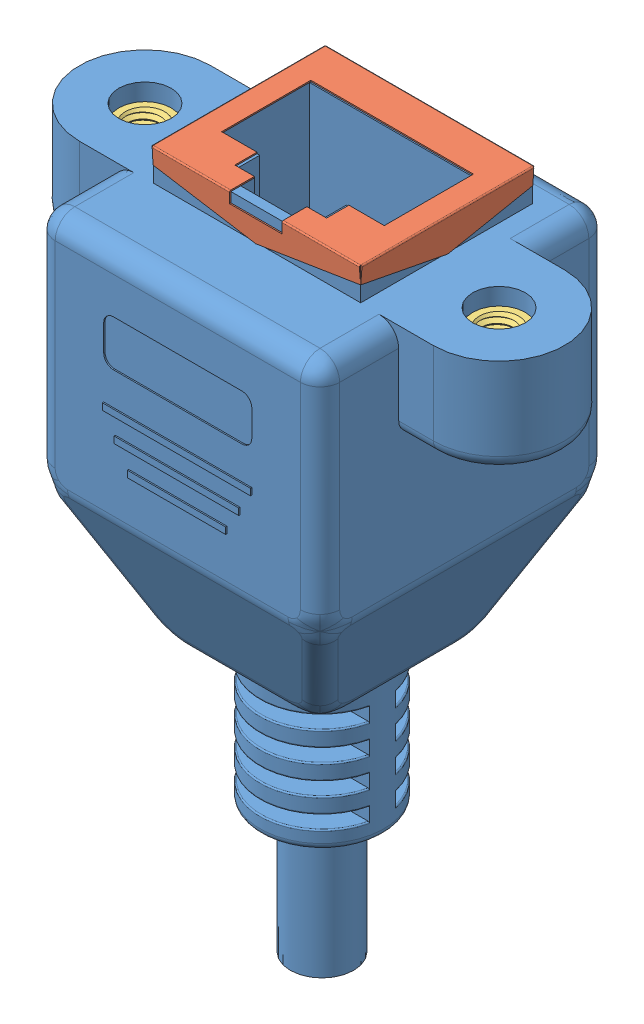
SolidWorks assembly RJ45 PanelMount, configuration Default. Lengths in mm.
Overall size (37 56.51 25.33).
4 component instances, 3 part files, 0 mates.
Components (placement in the parent):
- RJ45-1: RJ45 [Default] at origin size (37 51.7 22.31)
- MetalSheet-1: MetalSheet [Default] at origin size (27.86 12.02 25.16)
- M3 - nut 92497A200 v1-1: M3 - nut 92497A200 v1 [Default] at (0 -2.5 0) x (0.866025 0 -0.5) z (0 1 0) size (5.5 6.35 2.61)
- M3 - nut 92497A200 v1-2: M3 - nut 92497A200 v1 [Default] at (27 -2.5 0) x (0.866025 0 -0.5) z (0 1 0) size (5.5 6.35 2.61)
